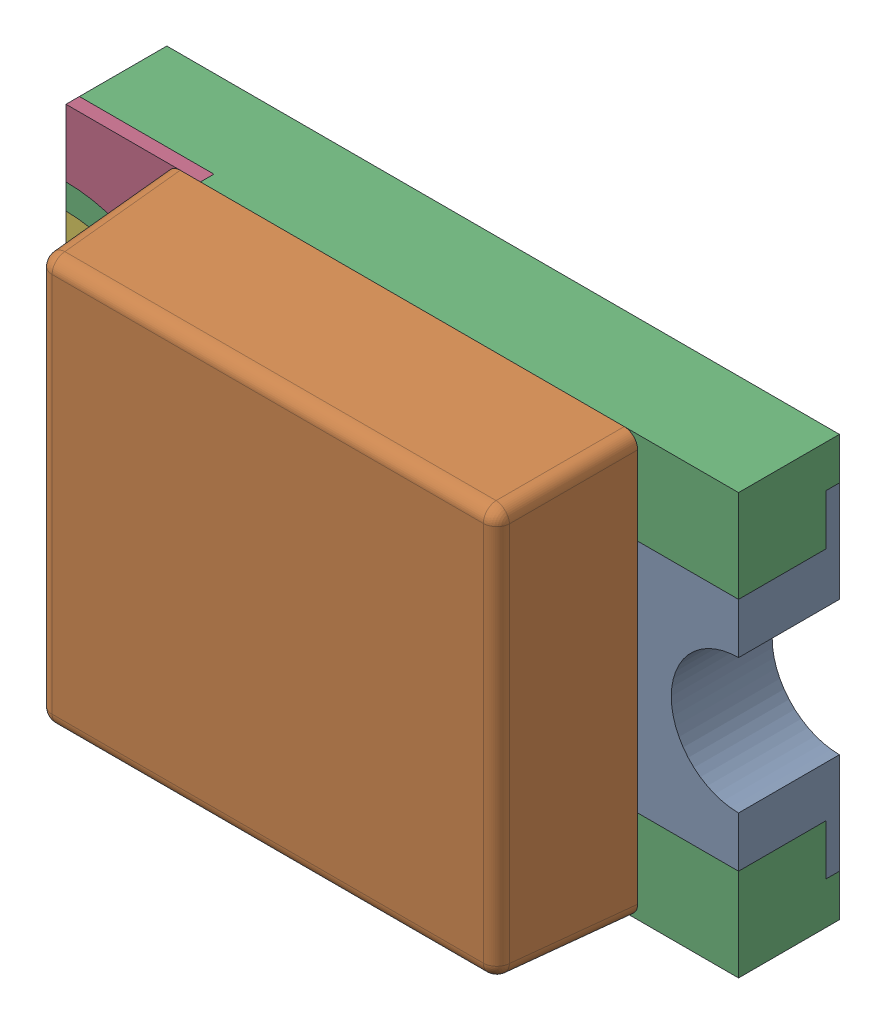
SolidWorks assembly D7, configuration Standard. Lengths in mm.
Overall size (2 1.25 0.7).
7 component instances, 5 part files, 0 mates.
Components (placement in the parent):
- WL-SMCW_0805_LED-1: WL-SMCW_0805_LED [Standard] at (12.0902 20.4702 -0.02) x (1 0 0) z (0 0 1) size (2 1.25 0.7)
  - base-1: base [Standard] at (0.8 0 0) x (-1 0 0) z (0 0 1) size (0.4 1 0.3)
  - cover-1: cover [Standard] at (0 0 0.3) size (1.4 1.25 0.4)
  - housing_3-1: housing_3 [Standard] at origin size (2 1.25 0.3)
  - marking-1: marking [Standard] at (-0.8 0.525 0.26) size (0.4 0.48 0.04)
  - marking-2: marking [Standard] at (-0.8 -0.525 0.3) x (1 0 0) z (0 0 -1) size (0.4 0.48 0.04)
  - base_2-1: base_2 [Standard] at (-0.8 0 0) size (0.4 1 0.3)
